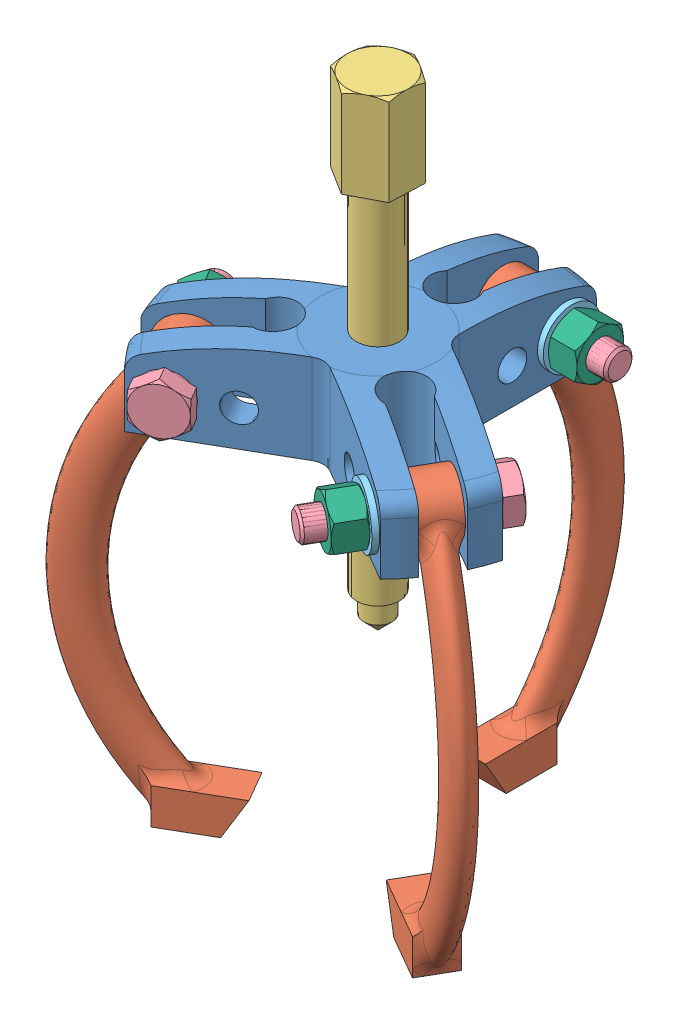
SolidWorks assembly ing_puller, configuration Predeterminado. Lengths in mm.
Overall size (122.75 187.38 114.75).
14 component instances, 6 part files, 27 mates.
Components (placement in the parent):
- bridge-1: bridge [Predeterminado] at origin size (96.93 30.15 85.37)
- Arm-1: Arm [Predeterminado] at (34.641 10 20) x (-0.866025 0 -0.5) z (0.5 0 -0.866025) size (42.69 118 11.01)
- Arm-3: Arm [Predeterminado] at (0 10 -40) x (0 0 1) z (-1 0 0) size (42.69 118 11.01)
- Arm-4: Arm [Predeterminado] at (-34.641 10 20) x (0.866025 0 -0.5) z (0.5 0 0.866025) size (42.69 118 11.01)
- wire_shaft-1: wire_shaft [Predeterminado] at (0 62.3727 0) size (17.81 135.01 19.62)
- hex bolt gradeab_din-2: hex bolt gradeab_din [ISO 4014 - M8 x 40 x 22-C] at (-17.8 10 -40) size (45.3 15.01 13)
- hex bolt gradeab_din-3: hex bolt gradeab_din [ISO 4014 - M8 x 40 x 22-C] at (43.541 10 4.5847) x (-0.5 0 0.866025) z (-0.866025 0 -0.5) size (45.3 15.01 13)
- hex bolt gradeab_din-4: hex bolt gradeab_din [ISO 4014 - M8 x 40 x 22-C] at (-25.741 10 35.4153) x (-0.5 0 -0.866025) z (0.866025 0 -0.5) size (45.3 15.01 13)
- plain washer grade a_din-2: plain washer grade a_din [Washer DIN 125 - A 8.4] at (12.5 10 -40) x (-1 0 0) z (0 0.924225 0.381849) size (1.6 16 16)
- plain washer grade a_din-3: plain washer grade a_din [Washer DIN 125 - A 8.4] at (28.391 10 30.8253) x (0.5 0 -0.866025) z (0.866025 0 0.5) size (1.6 16 16)
- plain washer grade a_din-4: plain washer grade a_din [Washer DIN 125 - A 8.4] at (-40.891 10 9.1747) x (0.5 0 0.866025) z (-0.866025 0 0.5) size (1.6 16 16)
- hex nut gradec_din-2: hex nut gradec_din [Hexagon Nut ISO 4034 - M8 - N] at (22 10 -40) x (0 0 -1) z (1 0 0) size (13 15.01 7.9)
- hex nut gradec_din-3: hex nut gradec_din [Hexagon Nut ISO 4034 - M8 - N] at (23.641 10 39.0526) x (0.866025 0 0.5) z (-0.5 0 0.866025) size (13 15.01 7.9)
- hex nut gradec_din-4: hex nut gradec_din [Hexagon Nut ISO 4034 - M8 - N] at (-45.641 10 0.9474) x (-0.866025 0 0.5) z (-0.5 0 -0.866025) size (13 15.01 7.9)
Mates (geometry in assembly coordinates):
- Coincidente2: coincident anti-aligned: plane of bridge-1 through (-18.5588 -165.7948 16.4884) normal (-0.5 0 -0.866025); plane of Arm-4 through (-32.141 10 24.3301) normal (0.5 0 0.866025)
- Concéntrica1: concentric anti-aligned: cylinder of bridge-1 through (-7.2223 10 67.4906) axis (-0.5 0 -0.866025) radius 4; cylinder of Arm-4 through (-37.3581 10 15.2939) axis (0.5 0 0.866025) radius 4
- Coincidente3: coincident anti-aligned: cylinder of bridge-1 through (-48.4529 10 -40) axis (1 0 0) radius 4; circle of Arm-3
- Coincidente4: coincident anti-aligned: plane of bridge-1 through (-5 -183.9646 -24.3166) normal (1 0 0); plane of Arm-3 through (-5 10 -40) normal (-1 0 0)
- Coincidente6: coincident anti-aligned: plane of bridge-1 through (18.5588 -165.7948 16.4884) normal (0.5 0 -0.866025); plane of Arm-1 through (32.141 10 24.3301) normal (-0.5 0 0.866025)
- Concéntrica2: concentric anti-aligned: cylinder of bridge-1 through (68.4263 10 -38.5179) axis (-0.5 0 0.866025) radius 4; cylinder of Arm-1 through (31.924 10 24.7061) axis (0.5 0 -0.866025) radius 4
- Coincidente7: coincident aligned: plane of Arm-4 through (-19.1506 -90 16.8301) normal (0 1 0); plane of Arm-3 through (-5 -90 -25) normal (0 1 0)
- Coincidente8: coincident aligned: plane of Arm-4 through (-19.1506 -90 16.8301) normal (0 1 0); plane of Arm-1 through (24.1506 -90 8.1699) normal (0 1 0)
- Concéntrica3: concentric aligned: cylinder of bridge-1 through (0 25 0) axis (0 1 0) radius 5.1; cylinder of wire_shaft-1 through (0 62.3727 0) axis (0 1 0) radius 6
- Concentric1: concentric anti-aligned: cylinder of bridge-1 through (-48.4529 10 -40) axis (1 0 0) radius 4; cylinder of hex bolt gradeab_din-2 through (-17.8 10 -40) axis (-1 0 0) radius 6.5
- Coincident1: coincident anti-aligned: plane of bridge-1 through (-12.5 178.6932 -10.1036) normal (-1 0 0); plane of hex bolt gradeab_din-2 through (-12.5 17.5056 -40) normal (1 0 0)
- Concentric2: concentric anti-aligned: cylinder of bridge-1 through (68.4263 10 -38.5179) axis (-0.5 0 0.866025) radius 4; cylinder of hex bolt gradeab_din-3 through (43.541 10 4.5847) axis (0.5 0 -0.866025) radius 6.5
- Coincident2: coincident anti-aligned: plane of bridge-1 through (15 179.5176 -5.7735) normal (0.5 0 -0.866025); plane of hex bolt gradeab_din-3 through (40.891 17.5056 9.1747) normal (-0.5 0 0.866025)
- Concentric3: concentric anti-aligned: cylinder of bridge-1 through (-7.2223 10 67.4906) axis (-0.5 0 -0.866025) radius 4; cylinder of hex bolt gradeab_din-4 through (-25.741 10 35.4153) axis (0.5 0 0.866025) radius 6.5
- Coincident3: coincident anti-aligned: plane of bridge-1 through (-2.5 178.6932 15.8771) normal (0.5 0 0.866025); plane of hex bolt gradeab_din-4 through (-28.391 17.5056 30.8253) normal (-0.5 0 -0.866025)
- Concentric5: concentric aligned: cylinder of bridge-1 through (-48.4529 10 -40) axis (1 0 0) radius 4; cylinder of plain washer grade a_din-2 through (47.425 10 -40) axis (1 0 0) radius 4.2
- Coincident4: coincident anti-aligned: plane of bridge-1 through (12.5 179.5176 -10.1036) normal (1 0 0); plane of plain washer grade a_din-2 through (12.5 8.3962 -36.1183) normal (-1 0 0)
- Concentric6: concentric aligned: cylinder of bridge-1 through (68.4263 10 -38.5179) axis (-0.5 0 0.866025) radius 4; cylinder of plain washer grade a_din-3 through (10.9285 10 61.0713) axis (-0.5 0 0.866025) radius 4.2
- Coincident5: coincident anti-aligned: plane of bridge-1 through (2.5 178.6932 15.8771) normal (-0.5 0 0.866025); plane of plain washer grade a_din-3 through (28.391 14.2 30.8253) normal (0.5 0 -0.866025)
- Concentric7: concentric aligned: cylinder of bridge-1 through (-7.2223 10 67.4906) axis (-0.5 0 -0.866025) radius 4; cylinder of plain washer grade a_din-4 through (-58.3535 10 -21.0713) axis (-0.5 0 -0.866025) radius 4.2
- Coincident6: coincident anti-aligned: plane of bridge-1 through (-15 178.6932 -5.7735) normal (-0.5 0 -0.866025); plane of plain washer grade a_din-4 through (-40.891 14.2 9.1747) normal (0.5 0 0.866025)
- Concentric9: concentric aligned: cylinder of plain washer grade a_din-2 through (47.425 10 -40) axis (1 0 0) radius 4.2; cylinder of hex nut gradec_din-2 through (-3.0375 10 -40) axis (1 0 0) radius 4
- Coincident7: coincident anti-aligned: plane of plain washer grade a_din-2 through (14.1 6.9452 -32.6062) normal (1 0 0); plane of hex nut gradec_din-2 through (14.1 17.5056 -40) normal (-1 0 0)
- Concentric10: concentric aligned: cylinder of plain washer grade a_din-3 through (10.9285 10 61.0713) axis (-0.5 0 0.866025) radius 8; cylinder of hex nut gradec_din-3 through (36.1598 10 17.3694) axis (-0.5 0 0.866025) radius 4
- Coincident8: coincident anti-aligned: plane of plain washer grade a_din-3 through (27.591 18 32.211) normal (-0.5 0 0.866025); plane of hex nut gradec_din-3 through (27.591 17.5056 32.211) normal (0.5 0 -0.866025)
- Concentric11: concentric aligned: cylinder of plain washer grade a_din-4 through (-58.3535 10 -21.0713) axis (-0.5 0 -0.866025) radius 8; cylinder of hex nut gradec_din-4 through (-33.1223 10 22.6306) axis (-0.5 0 -0.866025) radius 4
- Coincident9: coincident anti-aligned: plane of plain washer grade a_din-4 through (-41.691 18 7.789) normal (-0.5 0 -0.866025); plane of hex nut gradec_din-4 through (-41.691 17.5056 7.789) normal (0.5 0 0.866025)
